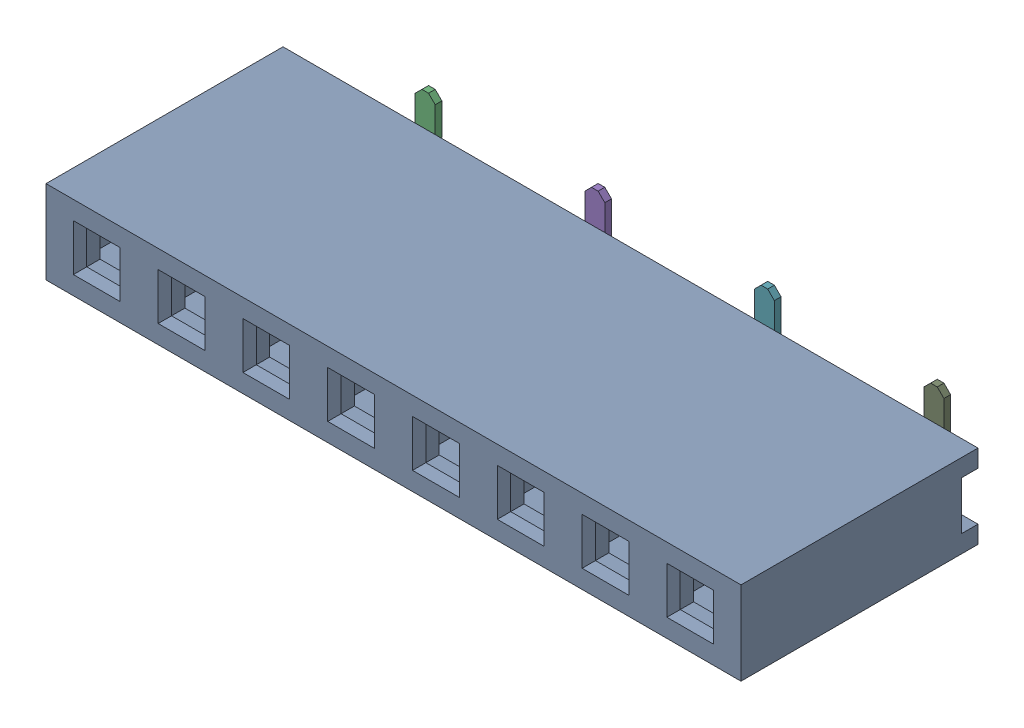
SolidWorks assembly 61000813321, configuration Default. Lengths in mm.
Overall size (20.82 4.05 7.5).
9 component instances, 2 part files, 0 mates.
Components (placement in the parent):
- 6100081xx21-1: 6100081xx21 [Default] at origin size (20.82 2.5 7.1)
- 6100xx1xx21_PIN-1: 6100xx1xx21_PIN [Default] at (-8.89 -0.725 -3.04) x (-1 0 0) z (0 0 -1) size (2 2.81 6.11)
- 6100xx1xx21_PIN-2: 6100xx1xx21_PIN [Default] at (-6.35 0.725 -3.04) x (1 0 0) z (0 0 -1) size (2 2.81 6.11)
- 6100xx1xx21_PIN-3: 6100xx1xx21_PIN [Default] at (-3.81 -0.725 -3.04) x (-1 0 0) z (0 0 -1) size (2 2.81 6.11)
- 6100xx1xx21_PIN-4: 6100xx1xx21_PIN [Default] at (-1.27 0.725 -3.04) x (1 0 0) z (0 0 -1) size (2 2.81 6.11)
- 6100xx1xx21_PIN-5: 6100xx1xx21_PIN [Default] at (1.27 -0.725 -3.04) x (-1 0 0) z (0 0 -1) size (2 2.81 6.11)
- 6100xx1xx21_PIN-6: 6100xx1xx21_PIN [Default] at (3.81 0.725 -3.04) x (1 0 0) z (0 0 -1) size (2 2.81 6.11)
- 6100xx1xx21_PIN-7: 6100xx1xx21_PIN [Default] at (6.35 -0.725 -3.04) x (-1 0 0) z (0 0 -1) size (2 2.81 6.11)
- 6100xx1xx21_PIN-8: 6100xx1xx21_PIN [Default] at (8.89 0.725 -3.04) x (1 0 0) z (0 0 -1) size (2 2.81 6.11)
